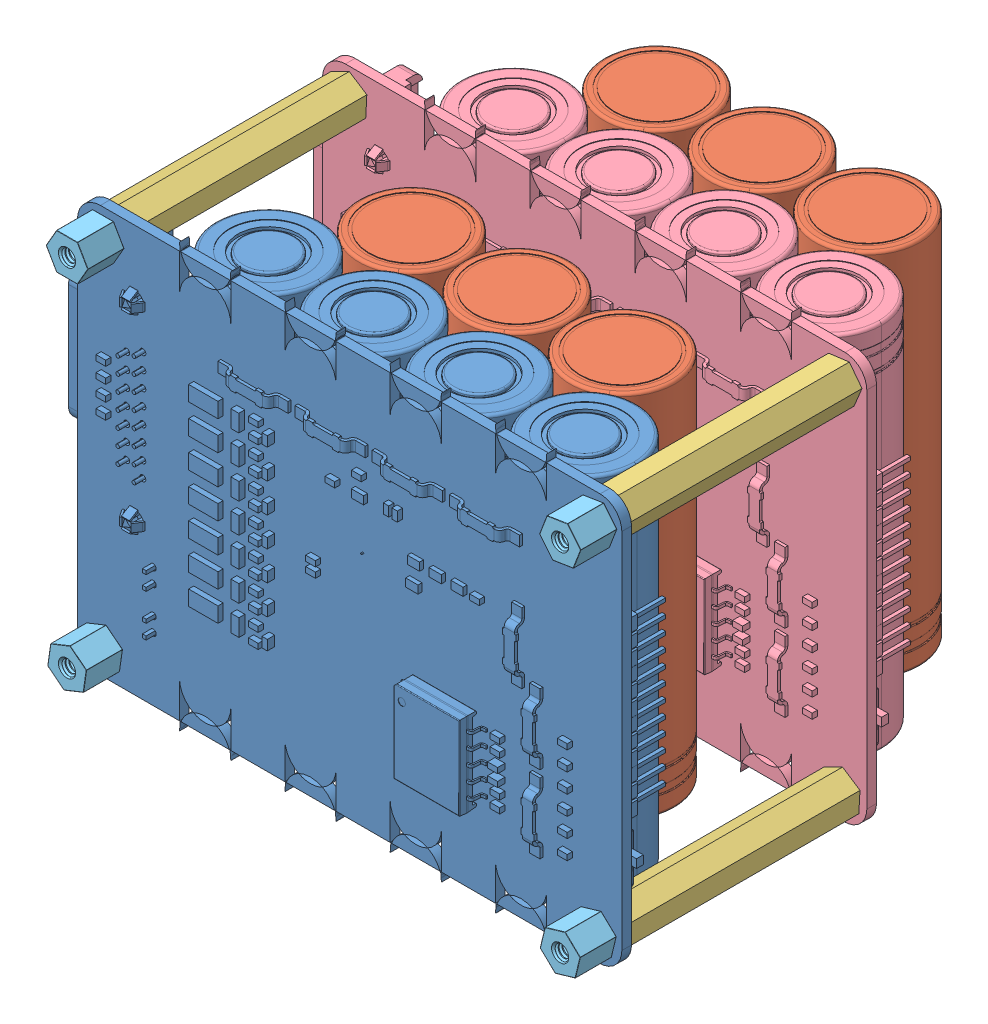
SolidWorks assembly FULL, configuration Default. Lengths in mm.
Overall size (101.63 76.75 89.18).
21 component instances, 5 part files, 28 mates.
Components (placement in the parent):
- 4501-WB_AV_BMS.step-1: 4501-WB_AV_BMS.step [Default] at origin (suppressed, hidden)
- 4501-WB_AV_BMS2.step-1: 4501-WB_AV_BMS2.step [Default] at origin size (101.3 76.75 23.6)
- Samsung 30Q 18650 Battery.step-1: Samsung 30Q 18650 Battery.step [Default] at (68.5612 68.0929 -27.0038) x (-0.571781 0 -0.820406) z (-0.820406 0 0.571781) size (18.4 65 18.4)
- Samsung 30Q 18650 Battery.step-2: Samsung 30Q 18650 Battery.step [Default] at (50.0612 68.0929 -27.0038) x (-0.571781 0 -0.820406) z (-0.820406 0 0.571781) size (18.4 65 18.4)
- Samsung 30Q 18650 Battery.step-3: Samsung 30Q 18650 Battery.step [Default] at (31.5612 68.0929 -27.0038) x (-0.571781 0 -0.820406) z (-0.820406 0 0.571781) size (18.4 65 18.4)
- Samsung 30Q 18650 Battery.step-4: Samsung 30Q 18650 Battery.step [Default] at (68.5612 68.0929 -69.0038) x (-0.571781 0 -0.820406) z (-0.820406 0 0.571781) size (18.4 65 18.4) (suppressed, hidden)
- 4501-WB_AV_BMS2.step-2: 4501-WB_AV_BMS2.step [Default] at (0 0 -42) size (101.3 76.75 23.6) (suppressed, hidden)
- Samsung 30Q 18650 Battery.step-5: Samsung 30Q 18650 Battery.step [Default] at (50.0612 68.0929 -69.0038) x (-0.571781 0 -0.820406) z (-0.820406 0 0.571781) size (18.4 65 18.4) (suppressed, hidden)
- Samsung 30Q 18650 Battery.step-6: Samsung 30Q 18650 Battery.step [Default] at (31.5612 68.0929 -69.0038) x (-0.571781 0 -0.820406) z (-0.820406 0 0.571781) size (18.4 65 18.4) (suppressed, hidden)
- Hex-Standoff-Threaded-#4-40-Aluminum-8410-1: Hex-Standoff-Threaded-#4-40-Aluminum-8410 [Default] at (90.9964 66.896 -1.6914) x (-0.788245 -0.615361 0) z (0.615361 -0.788245 0) size (6.38 46.03 7.33)
- 4501-WB_AV_BMS2-1: 4501-WB_AV_BMS2 [Default] at (0 0 -42.9714) size (101.3 76.75 23.6)
- Hex-Standoff-Threaded-#4-40-Aluminum-8410-2: Hex-Standoff-Threaded-#4-40-Aluminum-8410 [Default] at (90.9964 4.5 -1.6914) x (0.542648 0.83996 0) z (-0.83996 0.542648 0) size (6.38 46.03 7.33)
- Hex-Standoff-Threaded-#4-40-Aluminum-8410-4: Hex-Standoff-Threaded-#4-40-Aluminum-8410 [Default] at (4.5009 66.896 -1.6914) x (0.461205 -0.887294 0) z (0.887294 0.461205 0) size (6.38 46.03 7.33)
- Hex-Standoff-Threaded-#4-40-Aluminum-8410-5: Hex-Standoff-Threaded-#4-40-Aluminum-8410 [Default] at (4.5009 4.5 -1.6914) x (0.541904 -0.840441 0) z (0.840441 0.541904 0) size (6.38 46.03 7.33)
- Samsung 30Q 18650 Battery.step-7: Samsung 30Q 18650 Battery.step [Default] at (68.5612 68.0929 -70.0038) x (-0.571781 0 -0.820406) z (-0.820406 0 0.571781) size (18.4 65 18.4)
- Samsung 30Q 18650 Battery.step-8: Samsung 30Q 18650 Battery.step [Default] at (50.0612 68.0929 -70.0038) x (-0.571781 0 -0.820406) z (-0.820406 0 0.571781) size (18.4 65 18.4)
- Samsung 30Q 18650 Battery.step-9: Samsung 30Q 18650 Battery.step [Default] at (31.5612 68.0929 -70.0038) x (-0.571781 0 -0.820406) z (-0.820406 0 0.571781) size (18.4 65 18.4)
- 2100-440-AL.prt-1: 2100-440-AL.prt [Default] at (4.5009 66.896 0) x (0 0 -1) z (1 0 0) size (6.38 6.38 7.35)
- 2100-440-AL.prt-2: 2100-440-AL.prt [Default] at (90.9964 66.896 0) x (0 0 -1) z (0.987351 0.158553 0) size (6.38 6.38 7.35)
- 2100-440-AL.prt-3: 2100-440-AL.prt [Default] at (90.9964 4.5 0) x (0 0 -1) z (0.959125 0.282984 0) size (6.38 6.38 7.35)
- 2100-440-AL.prt-4: 2100-440-AL.prt [Default] at (4.5009 4.5 0) x (0 0 -1) z (0.928571 0.371154 0) size (6.38 6.38 7.35)
Mates (geometry in assembly coordinates):
- Coincident2: coincident: plane of 4501-WB_AV_BMS2.step-1 through (77.7966 68.0929 -11.0894) normal (0 1 0); plane of Samsung 30Q 18650 Battery.step-1 through (68.5612 68.0929 -27.0038) normal (0 1 0)
- Tangent3: tangent: cylinder of 4501-WB_AV_BMS2.step-1 through (77.7966 3.0929 -11.0894) axis (0 1 0) radius 9.2; cylinder of Samsung 30Q 18650 Battery.step-1 through (68.5612 68.0929 -27.0038) axis (0 -1 0) radius 9.2
- Tangent4: tangent: cylinder of 4501-WB_AV_BMS2.step-1 through (59.3257 3.0929 -11.0894) axis (0 1 0) radius 9.2; cylinder of Samsung 30Q 18650 Battery.step-1 through (68.5612 68.0929 -27.0038) axis (0 -1 0) radius 9.2
- Concentric3: concentric: cylinder of 4501-WB_AV_BMS2.step-1 through (90.9964 66.896 -1.6914) axis (0 0 -1) radius 1.6256; circle of Hex-Standoff-Threaded-#4-40-Aluminum-8410-1
- Coincident3: coincident: plane of 4501-WB_AV_BMS2.step-1 through (4.115 0 -1.6914) normal (0 0 -1); plane of Hex-Standoff-Threaded-#4-40-Aluminum-8410-1 through (90.9964 66.896 -1.6914) normal (0 0 1)
- Parallel3: parallel: plane of 4501-WB_AV_BMS2.step-1 through (95.466 3.899 -1.6914) normal (1 0 0); plane of 4501-WB_AV_BMS2-1 through (95.466 3.899 -44.6629) normal (1 0 0)
- Parallel4: parallel: plane of 4501-WB_AV_BMS2.step-1 through (91.656 71.364 -1.6914) normal (0 1 0); plane of 4501-WB_AV_BMS2-1 through (73.2965 71.364 -44.6629) normal (0 1 0)
- Concentric4: concentric: cylinder of 4501-WB_AV_BMS2.step-1 through (90.9964 66.896 -1.6914) axis (0 0 -1) radius 1.6256; cylinder of 4501-WB_AV_BMS2-1 through (90.9964 66.896 -44.6629) axis (0 0 -1) radius 1.6256
- Coincident7: coincident: plane of Hex-Standoff-Threaded-#4-40-Aluminum-8410-1 through (90.9964 66.896 -42.9714) normal (0 0 -1); plane of 4501-WB_AV_BMS2-1 through (4.115 0 -42.9714) normal (0 0 1)
- Concentric5: concentric: cylinder of 4501-WB_AV_BMS2.step-1 through (90.9964 4.5 -1.6914) axis (0 0 -1) radius 1.6256; circle of Hex-Standoff-Threaded-#4-40-Aluminum-8410-2
- Coincident8: coincident: plane of 4501-WB_AV_BMS2.step-1 through (4.115 0 -1.6914) normal (0 0 -1); plane of Hex-Standoff-Threaded-#4-40-Aluminum-8410-2 through (90.9964 4.5 -1.6914) normal (0 0 1)
- Coincident9: coincident: plane of 4501-WB_AV_BMS2-1 through (4.115 0 -42.9714) normal (0 0 1); plane of Hex-Standoff-Threaded-#4-40-Aluminum-8410-2 through (90.9964 4.5 -42.9714) normal (0 0 -1)
- Concentric6: concentric: cylinder of 4501-WB_AV_BMS2.step-1 through (4.5009 66.896 -1.6914) axis (0 0 -1) radius 1.6256; circle of Hex-Standoff-Threaded-#4-40-Aluminum-8410-4
- Coincident10: coincident: plane of 4501-WB_AV_BMS2.step-1 through (4.115 0 -1.6914) normal (0 0 -1); plane of Hex-Standoff-Threaded-#4-40-Aluminum-8410-4 through (4.5009 66.896 -1.6914) normal (0 0 1)
- Coincident11: coincident: plane of 4501-WB_AV_BMS2-1 through (4.115 0 -42.9714) normal (0 0 1); plane of Hex-Standoff-Threaded-#4-40-Aluminum-8410-4 through (4.5009 66.896 -42.9714) normal (0 0 -1)
- Coincident12: coincident: plane of 4501-WB_AV_BMS2.step-1 through (4.115 0 -1.6914) normal (0 0 -1); plane of Hex-Standoff-Threaded-#4-40-Aluminum-8410-5 through (4.5009 4.5 -1.6914) normal (0 0 1)
- Coincident13: coincident: plane of 4501-WB_AV_BMS2-1 through (4.115 0 -42.9714) normal (0 0 1); plane of Hex-Standoff-Threaded-#4-40-Aluminum-8410-5 through (4.5009 4.5 -42.9714) normal (0 0 -1)
- Concentric8: concentric: cylinder of 4501-WB_AV_BMS2.step-1 through (4.5009 4.5 -1.6914) axis (0 0 -1) radius 1.6256; circle of Hex-Standoff-Threaded-#4-40-Aluminum-8410-5
- Coincident14: coincident: plane of 4501-WB_AV_BMS2.step-1 through (4.115 0 -1.6914) normal (0 0 -1); plane of ? through (142.2567 100.5073 -1.6914) normal (0 0 1)
- Coincident15: coincident: plane of 4501-WB_AV_BMS2-1 through (4.115 0 -42.9714) normal (0 0 1); plane of ? through (142.2567 100.5073 -42.9714) normal (0 0 -1)
- Concentric9: concentric: circle of Hex-Standoff-Threaded-#4-40-Aluminum-8410-4; circle of 2100-440-AL.prt-1
- Coincident18: coincident: plane of 4501-WB_AV_BMS2.step-1 through (4.115 0 0) normal (0 0 1); plane of 2100-440-AL.prt-1 through (4.5009 66.896 0) normal (0 0 -1)
- Concentric10: concentric: circle of Hex-Standoff-Threaded-#4-40-Aluminum-8410-1; circle of 2100-440-AL.prt-2
- Coincident19: coincident: plane of 4501-WB_AV_BMS2.step-1 through (4.115 0 0) normal (0 0 1); plane of 2100-440-AL.prt-2 through (90.9964 66.896 0) normal (0 0 -1)
- Coincident20: coincident: plane of 4501-WB_AV_BMS2.step-1 through (4.115 0 0) normal (0 0 1); plane of 2100-440-AL.prt-3 through (90.9964 4.5 0) normal (0 0 -1)
- Concentric11: concentric: circle of Hex-Standoff-Threaded-#4-40-Aluminum-8410-2; circle of 2100-440-AL.prt-3
- Coincident21: coincident: plane of 4501-WB_AV_BMS2.step-1 through (4.115 0 0) normal (0 0 1); plane of 2100-440-AL.prt-4 through (4.5009 4.5 0) normal (0 0 -1)
- Concentric12: concentric: circle of Hex-Standoff-Threaded-#4-40-Aluminum-8410-5; circle of 2100-440-AL.prt-4
